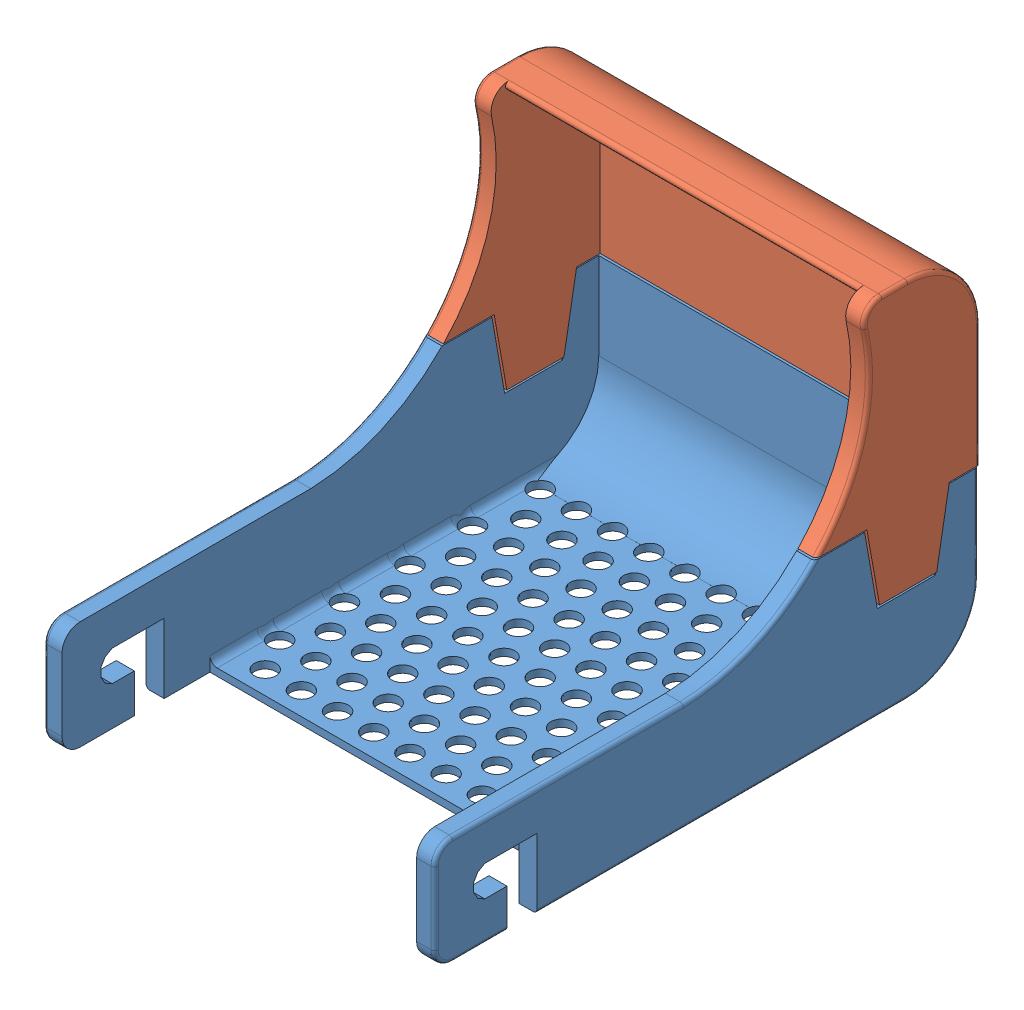
SolidWorks assembly Assem2, configuration Default. Lengths in mm.
Overall size (108.17 100.31 150.74).
2 component instances, 2 part files, 1 mates.
Components (placement in the parent):
- Tray top v2-1: Tray top v2 [Default] at (-8.1707 90.7352 140.9874) size (108.17 46 150.35)
- Tray bottom v2-1: Tray bottom v2 [Default] at (-8.1707 91.0433 140.5921) size (108.17 73.8 45.41)
Mates (geometry in assembly coordinates):
- Coincident1: coincident: plane of Tray top v2-1 through (100.8293 195.7352 232.3441) normal (1 0 0); plane of Tray bottom v2-1 through (100.8293 196.0433 231.9488) normal (1 0 0)
